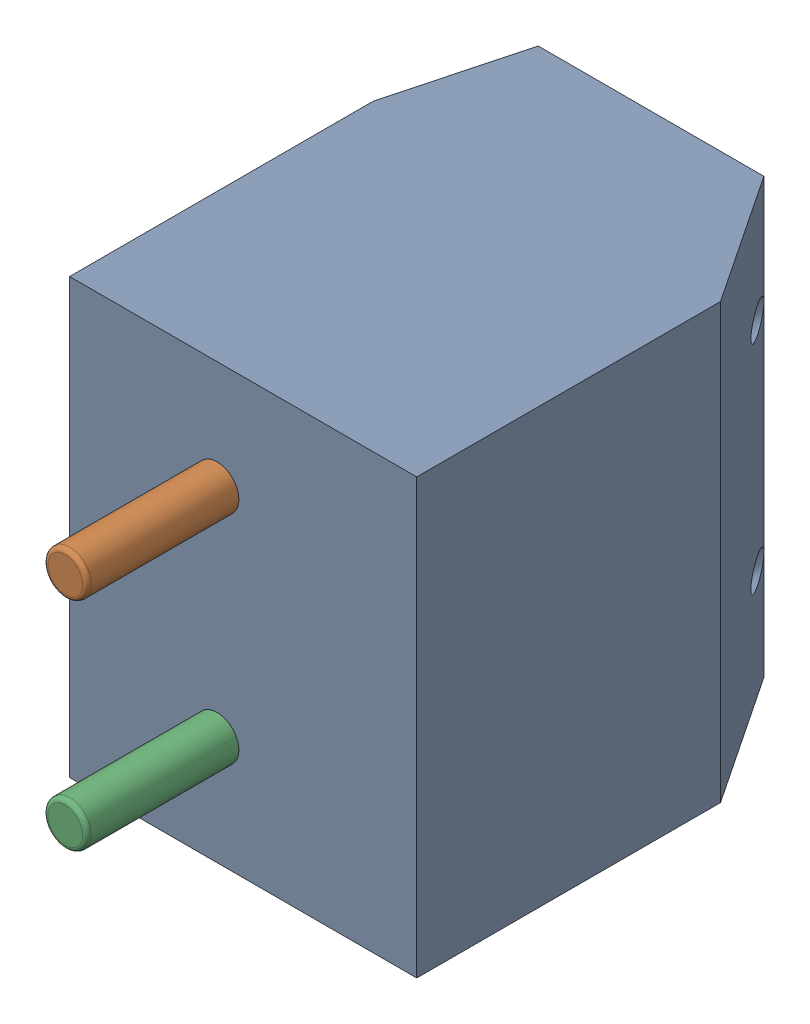
SolidWorks assembly J3, configuration Default. Lengths in mm.
Overall size (8 10 13.5).
4 component instances, 2 part files, 0 mates.
Components (placement in the parent):
- TB2-1: TB2 [Default] at (8.4073 32.4999 -11.7914) x (0 1 0) z (-1 0 0) size (10 13.5 8)
  - User_Library-TB2_TB_case_1-1: User_Library-TB2_TB_case_1 [Default] at (-10 0 0) x (0 0 1) z (0 1 0) size (8 10 10)
  - User_Library-TB2_TB_screw_1-1: User_Library-TB2_TB_screw_1 [Default] at (-2.5 -4.6 4.6) x (-1 0 0) z (0 0 -1) size (3.9 11.9 3.9)
  - User_Library-TB2_TB_screw_1-2: User_Library-TB2_TB_screw_1 [Default] at (-7.5 -4.6 4.6) size (3.9 11.9 3.9)
